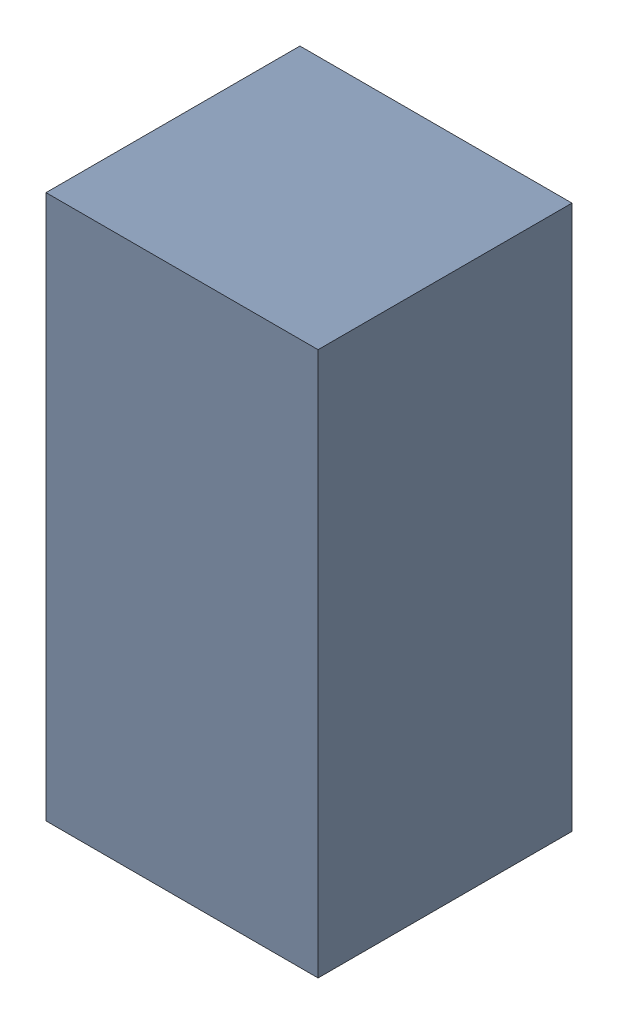
SolidWorks assembly IntPreKanaloa_v2.0.0_GPIO_b, configuration Default. Lengths in mm.
Overall size (1.5 3 1.4).
2 component instances, 1 part files, 0 mates.
Components (placement in the parent):
- 352878288-1: 352878288 [Default] at (101.981 62.357 2) size (1.5 3 1.4)
  - Extruded_1-1: Extruded_1 [Default] at origin size (1.5 3 1.4)
